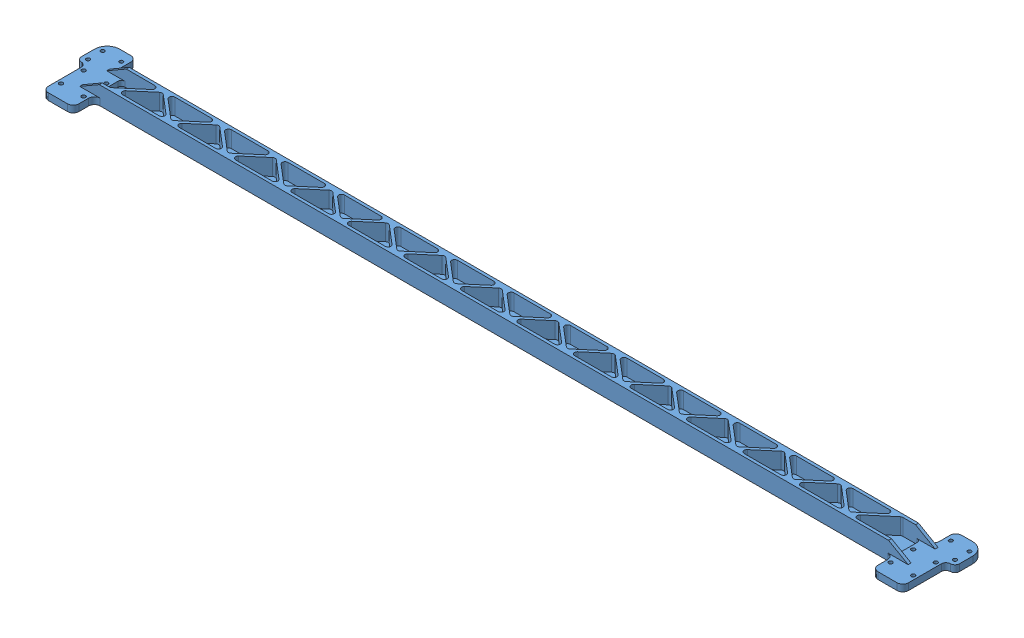
SolidWorks assembly crossbar_with_keep_nuts, configuration Aluminum Crossbar. Lengths in mm.
Overall size (777 25.4 65).
5 component instances, 2 part files, 8 mates.
Components (placement in the parent):
- m4_composite_insert_93918A102-1: m4_composite_insert_93918A102 [93918A102] at (-74.929 387.0105 24.0665) x (-0.969139 0 0.246516) z (-0.246516 0 -0.969139) (suppressed, hidden)
- m4_composite_insert_93918A102-2: m4_composite_insert_93918A102 [93918A102] at (-91.429 387.0105 36.8915) x (-0.293941 0 0.955824) z (-0.955824 0 -0.293941) (suppressed, hidden)
- m4_composite_insert_93918A102-3: m4_composite_insert_93918A102 [93918A102] at (370.571 387.0105 36.8915) x (0.866033 0 0.499986) z (-0.499986 0 0.866033) (suppressed, hidden)
- m4_composite_insert_93918A102-4: m4_composite_insert_93918A102 [93918A102] at (354.071 387.0105 24.0665) x (-0.759413 0 -0.650609) z (0.650609 0 -0.759413) (suppressed, hidden)
- crossbar_6mm_for_700mm_mgn12_rail-2: crossbar_6mm_for_700mm_mgn12_rail [Pocketed Crossbar] at (139.571 387.0105 61.3165) size (777 25.4 65)
Mates (geometry in assembly coordinates):
- Coincident1594070444: coincident aligned: plane of crossbar_6mm_for_400mm_mgn12_rail-1 through (139.571 393.0105 61.3165) normal (0 1 0); plane of m4_composite_insert_93918A102-1 through (-72.9908 393.0105 23.5734) normal (0 1 0)
- Concentric754009872: concentric aligned: cylinder of crossbar_6mm_for_400mm_mgn12_rail-1 through (-74.929 393.0105 24.0665) axis (0 -1 0) radius 5.9875; cylinder of m4_composite_insert_93918A102-1 through (-74.929 387.0105 24.0665) axis (0 -1 0) radius 6
- Coincident1594070445: coincident aligned: plane of crossbar_6mm_for_400mm_mgn12_rail-1 through (139.571 393.0105 61.3165) normal (0 1 0); plane of m4_composite_insert_93918A102-2 through (-90.8412 393.0105 34.9798) normal (0 1 0)
- Concentric754009873: concentric anti-aligned: circle of crossbar_6mm_for_400mm_mgn12_rail-1; circle of m4_composite_insert_93918A102-2
- Coincident1594070447: coincident aligned: plane of crossbar_6mm_for_400mm_mgn12_rail-1 through (139.571 393.0105 61.3165) normal (0 1 0); plane of m4_composite_insert_93918A102-3 through (368.8389 393.0105 35.8915) normal (0 1 0)
- Coincident1594070448: coincident aligned: plane of crossbar_6mm_for_400mm_mgn12_rail-1 through (139.571 393.0105 61.3165) normal (0 1 0); plane of m4_composite_insert_93918A102-4 through (355.5898 393.0105 25.3677) normal (0 1 0)
- Concentric754009876: concentric aligned: cylinder of crossbar_6mm_for_400mm_mgn12_rail-1 through (354.071 393.0105 24.0665) axis (0 -1 0) radius 5.9875; circle of m4_composite_insert_93918A102-4
- Concentric754010077: concentric aligned: cylinder of crossbar_6mm_for_400mm_mgn12_rail-1 through (370.571 393.0105 36.8915) axis (0 -1 0) radius 5.9875; cylinder of m4_composite_insert_93918A102-3 through (370.571 387.0105 36.8915) axis (0 -1 0) radius 6
